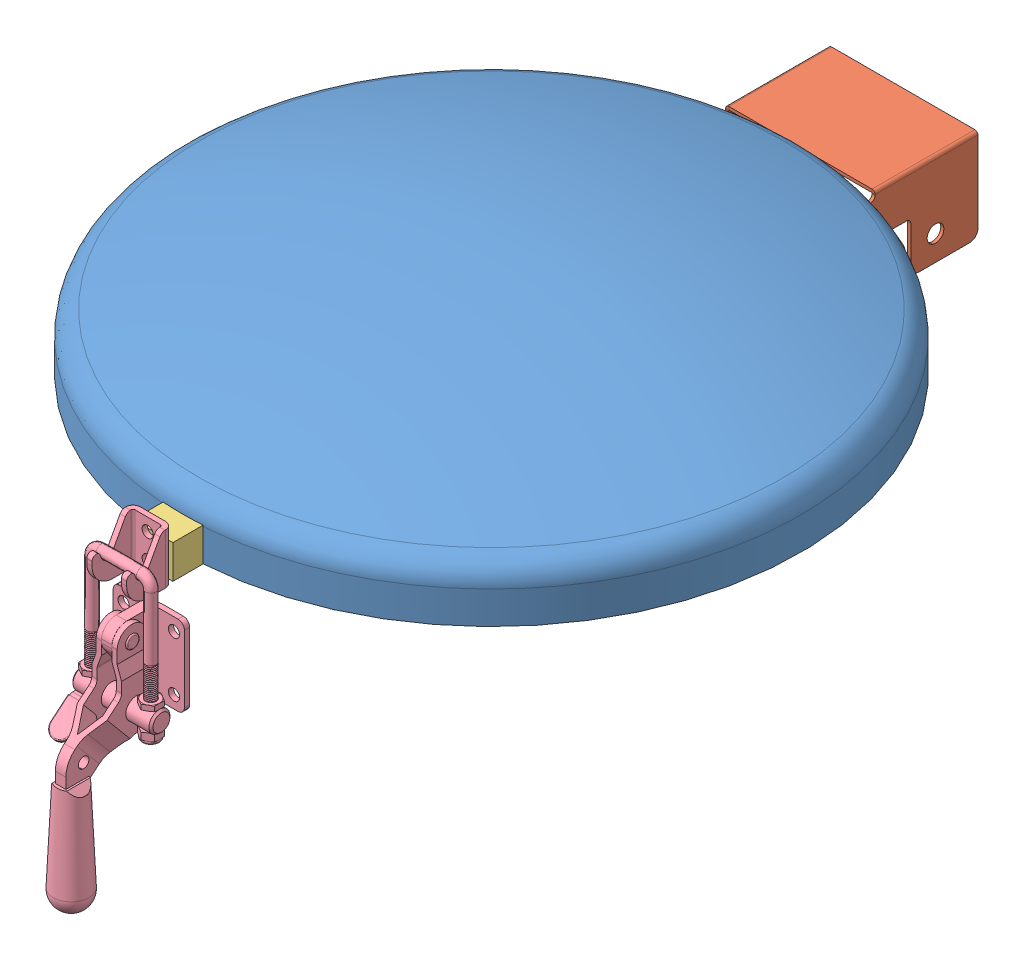
SolidWorks assembly Lid Assembly, configuration Default. Lengths in mm.
Overall size (548.2 438.64 642.51).
4 component instances, 4 part files, 8 mates.
Components (placement in the parent):
- Lid-2: Lid [Default] at (211.2181 -60.2546 -11.3558) x (0.978448 -0.106422 -0.176957) z (0.118934 -0.410093 0.904256) size (467.18 231.16 437.78)
- Stainless Hinge (Lid)-1: Stainless Hinge (Lid) [Default] at (0 31.628 -311.3405) x (-1 0 0) z (0 0 -1) size (198.67 69.73 99.8)
- Part1-1: Part1 [Default] at origin size (30.23 25.4 22.84)
- 5071A590-1: 5071A590 [Default] at (0.0381 -49.8475 255.0668) x (-1 0 0) z (0 1 0) size (60.86 76.1 227.53)
Mates (geometry in assembly coordinates):
- Coincident1: coincident anti-aligned: plane of Lid-2 through (12.368 0 230.0458) normal (0 -1 0); plane of assembly through (0 0 0) normal (0 1 0)
- Concentric1: concentric: cylinder of Lid-2 through (0 79.375 0) axis (0 1 0) radius 233.553; point of assembly
- Coincident3: coincident aligned: plane of Lid-2 through (12.368 0 230.0458) normal (0 -1 0); plane of Stainless Hinge (Lid)-1 through (54.1337 0 -260.5405) normal (0 -1 0)
- Coincident4: coincident anti-aligned: plane of Stainless Hinge (Lid)-1 through (0 31.628 -311.3405) normal (-1 0 0); plane of assembly through (0 0 0) normal (1 0 0)
- Tangent1: tangent anti-aligned: cylinder of Lid-2 through (0 79.375 0) axis (0 1 0) radius 233.553; plane of Stainless Hinge (Lid)-1 through (59.6583 29.2785 -233.553) normal (0 0 1)
- Distance1: distance = 1.5875 mm aligned: plane of 5071A590-1 through (0.0381 -1.5875 255.905) normal (0 -1 0); plane of Part1-1 through (0 0 0) normal (0 -1 0)
- Coincident6: coincident aligned: plane of Part1-1 through (15.113 25.4 233.0635) normal (1 0 0); plane of 5071A590-1 through (15.113 36.5125 290.83) normal (1 0 0)
- Coincident7: coincident anti-aligned: plane of Part1-1 through (15.113 25.4 255.905) normal (0 0 1); plane of 5071A590-1 through (9.5504 36.5125 255.905) normal (0 0 -1)
